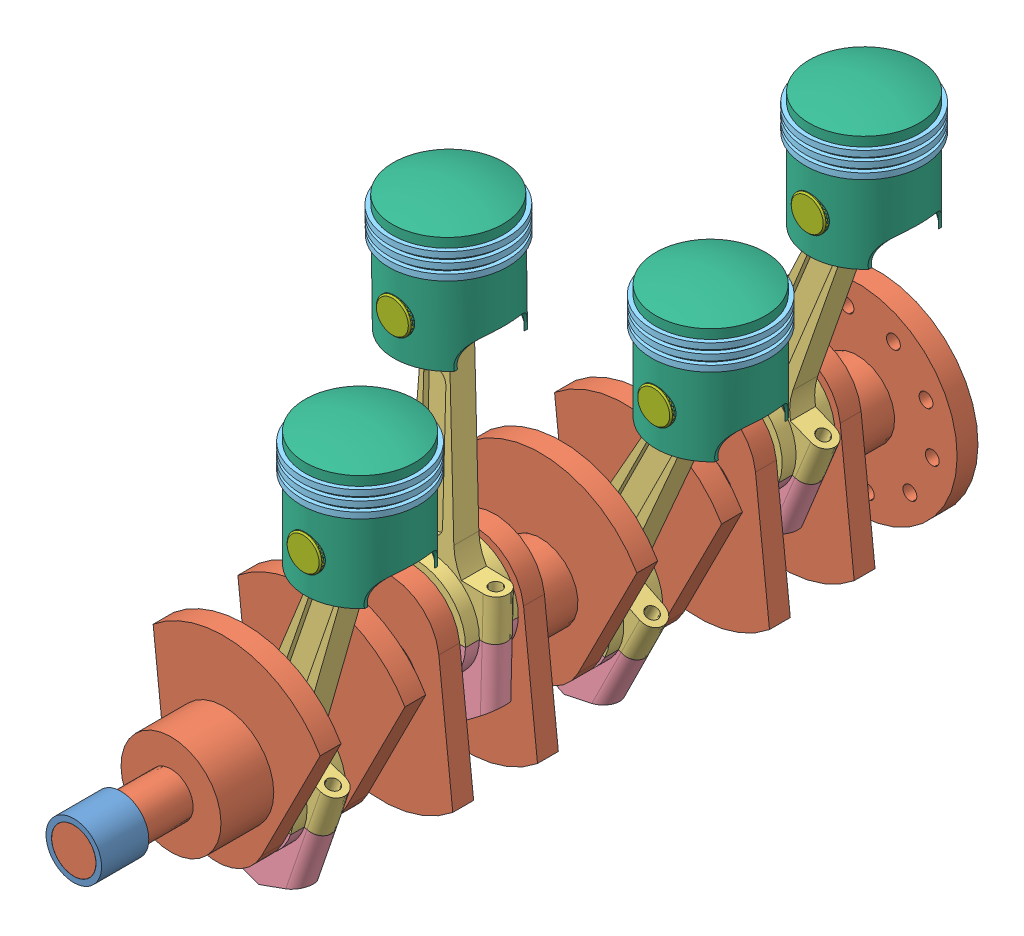
SolidWorks assembly AssemBLY OF MULTICYLINDER ENGINE, configuration Default. Lengths in mm.
Overall size (221.84 394.51 579).
34 component instances, 7 part files, 33 mates.
Components (placement in the parent):
- s1-1: s1 [Default] x (0 -1 0) z (-1 0 0) size (40 34 40)
- assembly crank shaft-1: assembly crank shaft [Default] at (0 0 17) x (0 0 -1) z (0.983749 -0.179549 0) size (579 160 144)
- assembly connecting rod-1: assembly connecting rod [Default] at (60.1084 162.8199 -129) x (0.946147 -0.323736 0) z (0 0 1) size (94 223.7 38)
- ASSEMBLY CONNECTING ROD CAP-1: ASSEMBLY CONNECTING ROD CAP [Default] at (-5.0274 -27.545 -148) x (0.946147 -0.323736 0) z (0 0 1) size (94 60 38)
- assembly connecting rod-2: assembly connecting rod [Default] at (10.383 228.6737 -243) x (0.999646 -0.026619 0) z (0 0 1) size (94 223.7 38)
- assembly connecting rod-3: assembly connecting rod [Default] at (84.5434 152.6175 -357) x (0.89544 -0.445183 0) z (0 0 1) size (94 223.7 38)
- assembly connecting rod-4: assembly connecting rod [Default] at (81.0197 213.8421 -471) x (0.92593 -0.377695 0) z (0 0 1) size (94 223.7 38)
- ASSEMBLY CONNECTING ROD CAP-2: ASSEMBLY CONNECTING ROD CAP [Default] at (-5.0274 -27.545 -376) x (0.89544 -0.445183 0) z (0 0 1) size (94 60 38)
- ASSEMBLY CONNECTING ROD CAP-3: ASSEMBLY CONNECTING ROD CAP [Default] at (5.0274 27.545 -490) x (0.92593 -0.377695 0) z (0 0 1) size (94 60 38)
- ASSEMBLY CONNECTING ROD CAP-4: ASSEMBLY CONNECTING ROD CAP [Default] at (5.0274 27.545 -262) x (0.999646 -0.026619 0) z (0 0 1) size (94 60 38)
- PISTON WITH RING AND PIN-1: PISTON WITH RING AND PIN [Default] at (56.0816 143.0971 -205.716) x (0.997722 0 -0.067454) z (0.067454 0 0.997722) size (85 91.79 85)
  - assembly piston ring-1: assembly piston ring [Default] at (-1.1571 50.7228 76.8129) size (85 4.3 85)
  - piston assembly-1: piston assembly [Default] at (-1.1571 -7.2772 76.8129) x (0.997722 0 0.067454) z (-0.067454 0 0.997722) size (79 91.79 79)
  - assembly piston ring-2: assembly piston ring [Default] at (-1.1571 64.7228 76.8129) size (85 4.3 85)
  - assembly piston ring-3: assembly piston ring [Default] at (-1.1571 57.7228 76.8129) size (85 4.3 85)
  - assembly piston pin-1: assembly piston pin [Default] at (1.6085 19.7228 35.9063) x (0.959077 0.275621 0.064841) z (0.274993 -0.961266 0.018592) size (25 82 25)
- PISTON WITH RING AND PIN-2: PISTON WITH RING AND PIN [Default] at (6.6369 208.8957 -319.716) x (0.997622 0.01418 -0.067454) z (0.067447 0.000959 0.997722) size (85 91.79 85)
  - assembly piston ring-1: assembly piston ring [Default] at (-1.1571 50.7228 76.8129) size (85 4.3 85)
  - piston assembly-1: piston assembly [Default] at (-1.1571 -7.2772 76.8129) x (0.997722 0 0.067454) z (-0.067454 0 0.997722) size (79 91.79 79)
  - assembly piston ring-2: assembly piston ring [Default] at (-1.1571 64.7228 76.8129) size (85 4.3 85)
  - assembly piston ring-3: assembly piston ring [Default] at (-1.1571 57.7228 76.8129) size (85 4.3 85)
  - assembly piston pin-1: assembly piston pin [Default] at (1.6085 19.7228 35.9063) x (0.959077 0.275621 0.064841) z (0.274993 -0.961266 0.018592) size (25 82 25)
- PISTON WITH RING AND PIN-3: PISTON WITH RING AND PIN [Default] at (76.9928 194.1193 -547.716) x (0.997722 0 -0.067454) z (0.067454 0 0.997722) size (85 91.79 85)
  - assembly piston ring-1: assembly piston ring [Default] at (-1.1571 50.7228 76.8129) size (85 4.3 85)
  - piston assembly-1: piston assembly [Default] at (-1.1571 -7.2772 76.8129) x (0.997722 0 0.067454) z (-0.067454 0 0.997722) size (79 91.79 79)
  - assembly piston ring-2: assembly piston ring [Default] at (-1.1571 64.7228 76.8129) size (85 4.3 85)
  - assembly piston ring-3: assembly piston ring [Default] at (-1.1571 57.7228 76.8129) size (85 4.3 85)
  - assembly piston pin-1: assembly piston pin [Default] at (1.6085 19.7228 35.9063) x (0.959077 0.275621 0.064841) z (0.274993 -0.961266 0.018592) size (25 82 25)
- PISTON WITH RING AND PIN-4: PISTON WITH RING AND PIN [Default] at (80.5166 132.8947 -433.716) x (0.997722 0 -0.067454) z (0.067454 0 0.997722) size (85 91.79 85)
  - assembly piston ring-1: assembly piston ring [Default] at (-1.1571 50.7228 76.8129) size (85 4.3 85)
  - piston assembly-1: piston assembly [Default] at (-1.1571 -7.2772 76.8129) x (0.997722 0 0.067454) z (-0.067454 0 0.997722) size (79 91.79 79)
  - assembly piston ring-2: assembly piston ring [Default] at (-1.1571 64.7228 76.8129) size (85 4.3 85)
  - assembly piston ring-3: assembly piston ring [Default] at (-1.1571 57.7228 76.8129) size (85 4.3 85)
  - assembly piston pin-1: assembly piston pin [Default] at (1.6085 19.7228 35.9063) x (0.959077 0.275621 0.064841) z (0.274993 -0.961266 0.018592) size (25 82 25)
Mates (geometry in assembly coordinates):
- Coincident1: coincident: plane of s1-1 through (0 0 0) normal (0 0 1); plane of assembly through (0 0 0) normal (0 0 1)
- Coincident3: coincident: plane of s1-1 through (0 0 0) normal (-1 0 0); plane of assembly through (0 0 0) normal (1 0 0)
- Coincident4: coincident: plane of s1-1 through (0 0 0) normal (0 -1 0); plane of assembly through (0 0 0) normal (0 1 0)
- Concentric1: concentric: cylinder of s1-1 through (0 0 17) axis (0 0 -1) radius 16; cylinder of assembly crank shaft-1 through (0 0 -53) axis (0 0 1) radius 16
- Coincident5: coincident: plane of s1-1 through (0 0 17) normal (0 0 1); plane of assembly crank shaft-1 through (0 0 17) normal (0 0 1)
- Concentric2: concentric: cylinder of assembly connecting rod-1 through (103.3461 171.8062 -129) axis (-0.323736 -0.946147 0) radius 4.5; cylinder of ASSEMBLY CONNECTING ROD CAP-1 through (11.5021 -96.6158 -129) axis (0.323736 0.946147 0) radius 4.5
- Concentric3: concentric: cylinder of assembly connecting rod-1 through (31.4389 196.4102 -129) axis (-0.323736 -0.946147 0) radius 4.5; cylinder of ASSEMBLY CONNECTING ROD CAP-1 through (-60.4051 -72.0118 -129) axis (0.323736 0.946147 0) radius 4.5
- Coincident6: coincident: plane of assembly connecting rod-1 through (-39.0887 -15.8905 -110) normal (-0.323736 -0.946147 0); plane of ASSEMBLY CONNECTING ROD CAP-1 through (20.5186 -36.2859 -110) normal (0.323736 0.946147 0)
- Concentric4: concentric: cylinder of assembly crank shaft-1 through (-5.0274 -27.545 -152) axis (0 0 1) radius 27; cylinder of ASSEMBLY CONNECTING ROD CAP-1 through (-5.0274 -27.545 -150) axis (0 0 1) radius 27
- Width1: width: plane of assembly connecting rod-1 through (-5.0274 -27.545 -148) normal (0 0 -1); plane of assembly connecting rod-1 through (-5.0274 -27.545 -110) normal (0 0 1); plane of assembly crank shaft-1 through (-5.0274 -27.545 -106) normal (0 0 -1); plane of assembly crank shaft-1 through (-5.0274 -27.545 -152) normal (0 0 1)
- Concentric5: concentric: cylinder of assembly connecting rod-2 through (48.9685 250.1542 -243) axis (-0.026619 -0.999646 0) radius 4.5; cylinder of ASSEMBLY CONNECTING ROD CAP-4 through (41.4168 -33.4453 -243) axis (0.026619 0.999646 0) radius 4.5
- Concentric6: concentric: cylinder of assembly connecting rod-2 through (-27.0046 252.1772 -243) axis (-0.026619 -0.999646 0) radius 4.5; cylinder of ASSEMBLY CONNECTING ROD CAP-4 through (-34.5563 -31.4223 -243) axis (0.026619 0.999646 0) radius 4.5
- Coincident7: coincident: plane of assembly connecting rod-2 through (-30.9599 28.5032 -224) normal (-0.026619 -0.999646 0); plane of ASSEMBLY CONNECTING ROD CAP-4 through (32.0178 26.8263 -224) normal (0.026619 0.999646 0)
- Concentric7: concentric: cylinder of assembly crank shaft-1 through (5.0274 27.545 -266) axis (0 0 1) radius 27; cylinder of ASSEMBLY CONNECTING ROD CAP-4 through (5.0274 27.545 -264) axis (0 0 1) radius 27
- Width2: width: plane of assembly crank shaft-1 through (5.0274 27.545 -220) normal (0 0 -1); plane of assembly crank shaft-1 through (0 0 -266) normal (0 0 1); plane of assembly connecting rod-2 through (5.0274 27.545 -262) normal (0 0 -1); plane of assembly connecting rod-2 through (5.0274 27.545 -224) normal (0 0 1)
- Concentric8: concentric: cylinder of assembly connecting rod-3 through (128.5867 155.848 -357) axis (-0.445183 -0.89544 0) radius 4.5; cylinder of ASSEMBLY CONNECTING ROD CAP-2 through (2.2884 -98.1883 -357) axis (0.445183 0.89544 0) radius 4.5
- Concentric9: concentric: cylinder of assembly connecting rod-3 through (60.5333 189.6818 -357) axis (-0.445183 -0.89544 0) radius 4.5; cylinder of ASSEMBLY CONNECTING ROD CAP-2 through (-65.765 -64.3544 -357) axis (0.445183 0.89544 0) radius 4.5
- Coincident8: coincident: plane of assembly connecting rod-3 through (-37.2632 -11.5184 -338) normal (-0.445183 -0.89544 0); plane of ASSEMBLY CONNECTING ROD CAP-2 through (19.1495 -39.5649 -338) normal (0.445183 0.89544 0)
- Concentric10: concentric: cylinder of assembly crank shaft-1 through (-5.0274 -27.545 -380) axis (0 0 1) radius 27; cylinder of ASSEMBLY CONNECTING ROD CAP-2 through (-5.0274 -27.545 -378) axis (0 0 1) radius 27
- Width3: width: plane of assembly crank shaft-1 through (-5.0274 -27.545 -334) normal (0 0 -1); plane of assembly crank shaft-1 through (0 0 -380) normal (0 0 1); plane of assembly connecting rod-3 through (-5.0274 -27.545 -338) normal (0 0 1); plane of assembly connecting rod-3 through (-5.0274 -27.545 -376) normal (0 0 -1)
- Concentric11: concentric: cylinder of assembly connecting rod-4 through (124.7032 220.3231 -471) axis (-0.377695 -0.92593 0) radius 4.5; cylinder of ASSEMBLY CONNECTING ROD CAP-3 through (17.551 -42.3632 -471) axis (0.377695 0.92593 0) radius 4.5
- Concentric12: concentric: cylinder of assembly connecting rod-4 through (54.3325 249.0279 -471) axis (-0.377695 -0.92593 0) radius 4.5; cylinder of ASSEMBLY CONNECTING ROD CAP-3 through (-52.8197 -13.6584 -471) axis (0.377695 0.92593 0) radius 4.5
- Coincident9: coincident: plane of assembly connecting rod-4 through (-28.3061 41.142 -452) normal (-0.377695 -0.92593 0); plane of ASSEMBLY CONNECTING ROD CAP-3 through (30.0275 17.3472 -452) normal (0.377695 0.92593 0)
- Concentric13: concentric: cylinder of assembly crank shaft-1 through (5.0274 27.545 -494) axis (0 0 1) radius 27; cylinder of ASSEMBLY CONNECTING ROD CAP-3 through (5.0274 27.545 -492) axis (0 0 1) radius 27
- Width4: width: plane of assembly crank shaft-1 through (5.0274 27.545 -448) normal (0 0 -1); plane of assembly crank shaft-1 through (5.0274 27.545 -494) normal (0 0 1); plane of ASSEMBLY CONNECTING ROD CAP-3 through (5.0274 27.545 -452) normal (0 0 1); plane of ASSEMBLY CONNECTING ROD CAP-3 through (5.0274 27.545 -490) normal (0 0 -1)
- Concentric14: concentric: cylinder of assembly connecting rod-1 through (60.1084 162.8199 -148) axis (0 0 1) radius 12.5; cylinder of PISTON WITH RING AND PIN-1/piston assembly-1 through (60.1084 162.8199 -89.5) axis (0 0 -1) radius 12.5
- Width5: width: plane of PISTON WITH RING AND PIN-1/assembly piston pin-1 through (60.1084 162.8199 -170) normal (0 0 -1); plane of PISTON WITH RING AND PIN-1/assembly piston pin-1 through (60.1084 162.8199 -88) normal (0 0 1); plane of assembly connecting rod-1 through (60.1084 162.8199 -148) normal (0 0 -1); plane of assembly connecting rod-1 through (60.1084 162.8199 -110) normal (0 0 1)
- Concentric15: concentric: cylinder of assembly connecting rod-2 through (10.383 228.6737 -262) axis (0 0 1) radius 12.5; cylinder of PISTON WITH RING AND PIN-2/assembly piston pin-1 through (10.383 228.6737 -202) axis (0 0 -1) radius 12.5
- Width6: width: plane of assembly connecting rod-2 through (10.383 228.6737 -262) normal (0 0 -1); plane of assembly connecting rod-2 through (10.383 228.6737 -224) normal (0 0 1); plane of PISTON WITH RING AND PIN-2/assembly piston pin-1 through (10.383 228.6737 -202) normal (0 0 1); plane of PISTON WITH RING AND PIN-2/assembly piston pin-1 through (10.383 228.6737 -284) normal (0 0 -1)
- Concentric16: concentric: cylinder of assembly connecting rod-3 through (84.5434 152.6175 -376) axis (0 0 1) radius 12.5; cylinder of PISTON WITH RING AND PIN-4/assembly piston pin-1 through (84.5434 152.6175 -316) axis (0 0 -1) radius 12.5
- Width7: width: plane of assembly connecting rod-3 through (84.5434 152.6175 -338) normal (0 0 1); plane of assembly connecting rod-3 through (84.5434 152.6175 -376) normal (0 0 -1); plane of PISTON WITH RING AND PIN-4/assembly piston pin-1 through (84.5434 152.6175 -398) normal (0 0 -1); plane of PISTON WITH RING AND PIN-4/assembly piston pin-1 through (84.5434 152.6175 -316) normal (0 0 1)
- Concentric17: concentric: cylinder of assembly connecting rod-4 through (81.0197 213.8421 -490) axis (0 0 1) radius 12.5; cylinder of PISTON WITH RING AND PIN-3/assembly piston pin-1 through (81.0197 213.8421 -430) axis (0 0 -1) radius 12.5
- Width8: width: plane of assembly connecting rod-4 through (81.0197 213.8421 -452) normal (0 0 1); plane of assembly connecting rod-4 through (81.0197 213.8421 -490) normal (0 0 -1); plane of PISTON WITH RING AND PIN-3/assembly piston pin-1 through (81.0197 213.8421 -430) normal (0 0 1); plane of PISTON WITH RING AND PIN-3/assembly piston pin-1 through (81.0197 213.8421 -512) normal (0 0 -1)
